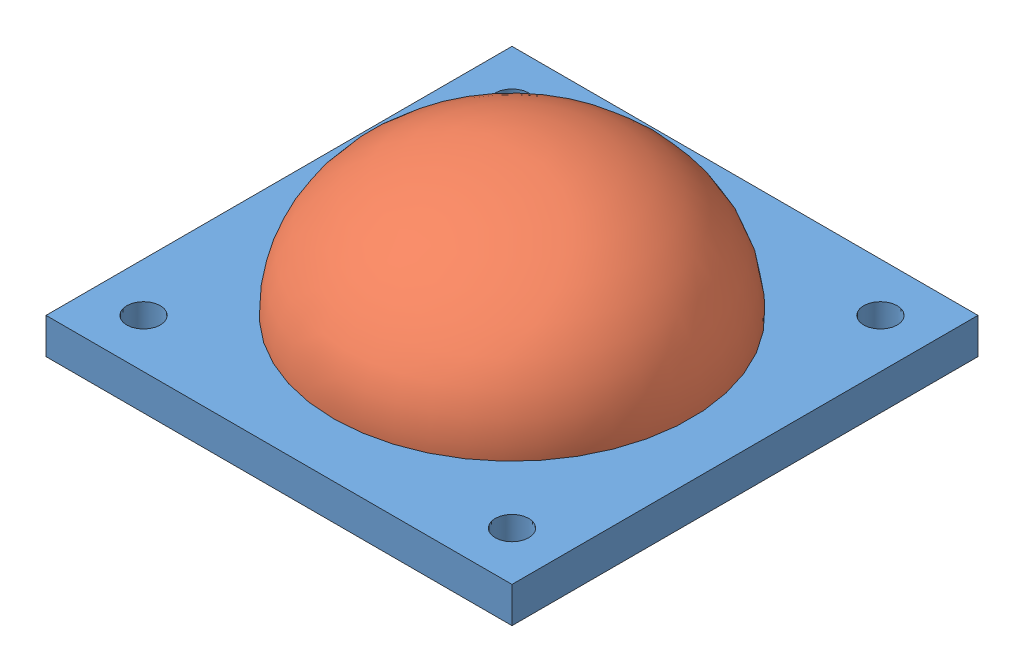
SolidWorks assembly Assem3, configuration Default. Lengths in mm.
Overall size (43 16.6 43).
2 component instances, 2 part files, 2 mates.
Components (placement in the parent):
- osnova-1: osnova [Default] at (-1.4803 17.5129 13.88) x (1 0 0) z (0 -1 0) size (43 43 3.3)
- kupol-v3-0.6mm-1: kupol-v3-0.6mm [Default] at (20.0197 24.163 68.38) size (33 13.3 33)
Mates (geometry in assembly coordinates):
- Coincident1: coincident: plane of osnova-1 through (-1.4803 17.5129 13.88) normal (0 1 0); plane of kupol-v3-0.6mm-1 through (20.0197 17.5129 51.8746) normal (0 -1 0)
- Concentric1: concentric: circle of osnova-1; circle of kupol-v3-0.6mm-1
